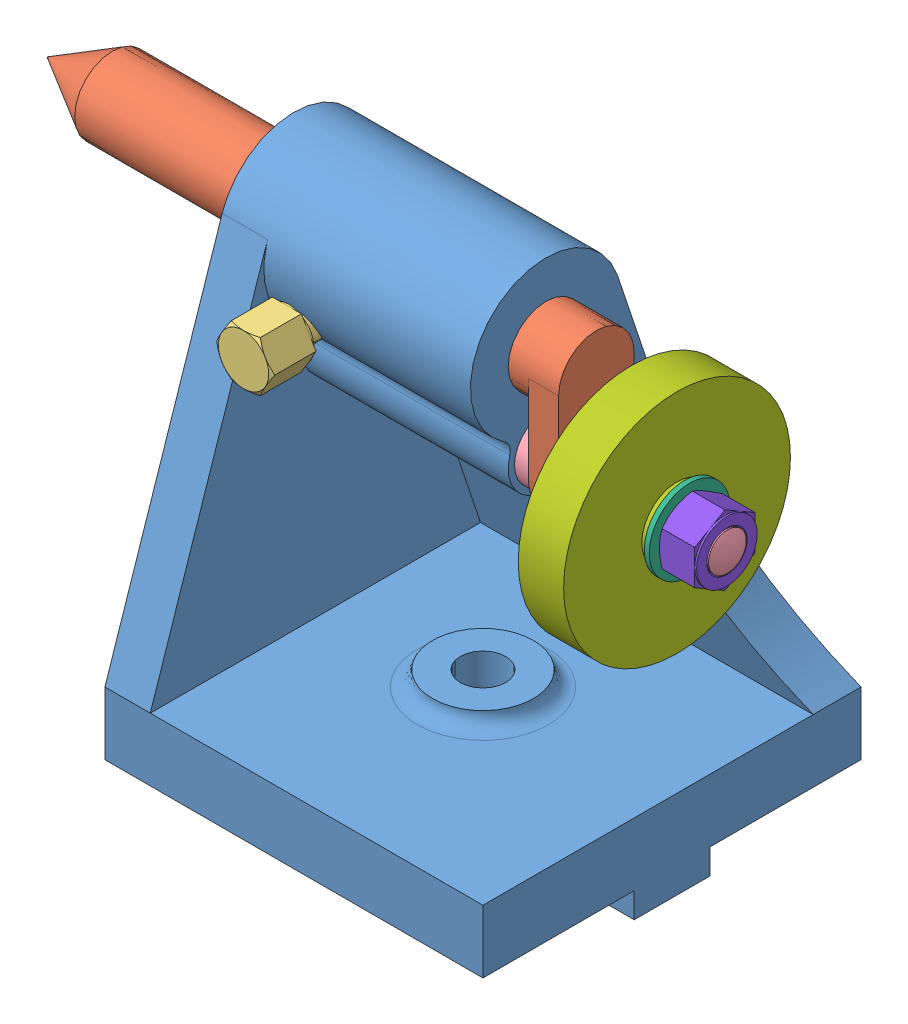
SolidWorks assembly Assem1, configuration Default. Lengths in mm.
Overall size (271.75 195 150).
8 component instances, 8 part files, 18 mates.
Components (placement in the parent):
- Part1-1: Part1 [Default] at (-27.6398 43.1033 183.0792) size (150 195 150)
- Part2-2: Part2 [Default] at (17.3602 198.1033 183.0792) x (0 -1 0) z (0 0 -1) size (65 217.98 30)
- Part3-2: Part3 [PreviewCfg] at (-72.6398 183.1033 233.0792) x (0 0 -1) z (0 -1 0) size (88 23.09 20)
- Part4-2: Part4 [Default] at (1.3602 163.1033 183.0792) size (135.54 25 25)
- Part5-2: Part5 [Default] at (34.8602 170.6033 183.0792) size (35 5 5)
- Part6-2: Part6 [Default] at (53.3602 163.1033 183.0792) x (0 -0.957696 -0.287782) z (1 0 0) size (32 32 2)
- Part7-2: Part7 [Default] at (40.3602 163.1033 183.0792) x (0 0 1) z (-1 0 0) size (90 90 35)
- hex nut style 1 gradeab_iso-1: hex nut style 1 gradeab_iso [ISO - 4032 - M16 - W - N] at (54.3602 163.1033 183.0792) x (0 0 1) z (-1 0 0) size (24 27.71 14.8)
Mates (geometry in assembly coordinates):
- Concentric3: concentric aligned: cylinder of Part1-1 through (-72.6398 183.1033 108.0792) axis (0 0 1) radius 6; cylinder of Part3-2 through (-72.6398 183.1033 233.0792) axis (0 0 1) radius 6
- Concentric5: concentric anti-aligned: cylinder of Part1-1 through (-2.6398 198.1033 183.0792) axis (-1 0 0) radius 15; cylinder of Part3-2 through (-84.1869 198.1033 183.0792) axis (1 0 0) radius 15
- Concentric6: concentric anti-aligned: cylinder of Part1-1 through (-72.6398 163.1033 183.0792) axis (1 0 0) radius 7.5; cylinder of Part4-2 through (-79.3247 163.1033 183.0792) axis (-1 0 0) radius 7.5
- Concentric7: concentric anti-aligned: cylinder of Part1-1 through (-2.6398 198.1033 183.0792) axis (-1 0 0) radius 15; cylinder of Part2-2 through (5.3602 198.1033 183.0792) axis (1 0 0) radius 15
- Concentric8: concentric anti-aligned: cylinder of Part2-2 through (5.3602 163.1033 183.0792) axis (1 0 0) radius 7.5; cylinder of Part4-2 through (-79.3247 163.1033 183.0792) axis (-1 0 0) radius 7.5
- Coincident2: coincident anti-aligned: plane of Part2-2 through (5.3602 198.1033 183.0792) normal (-1 0 0); plane of Part4-2 through (5.3602 163.1033 183.0792) normal (1 0 0)
- Coincident3: coincident anti-aligned: plane of Part4-2 through (52.3602 168.1033 180.5792) normal (0 1 0); plane of Part5-2 through (52.3602 168.1033 185.5792) normal (0 -1 0)
- Coincident4: coincident anti-aligned: plane of Part4-2 through (52.3602 173.1033 180.5792) normal (-1 0 0); plane of Part5-2 through (52.3602 173.1033 185.5792) normal (1 0 0)
- Coincident5: coincident anti-aligned: plane of Part4-2 through (1.3602 163.1033 185.5792) normal (0 0 -1); plane of Part5-2 through (34.8602 170.6033 185.5792) normal (0 0 1)
- Concentric9: concentric aligned: cylinder of Part4-2 through (-79.3247 163.1033 183.0792) axis (-1 0 0) radius 7.5; cylinder of Part7-2 through (-2.4238 163.1033 183.0792) axis (-1 0 0) radius 7.5
- Coincident6: coincident anti-aligned: plane of Part5-2 through (17.3602 172.7533 185.5792) normal (-0.01 0.99995 0); plane of Part7-2 through (52.3602 173.1033 180.5792) normal (0.01 -0.99995 0)
- Concentric10: concentric aligned: cylinder of Part4-2 through (-79.3247 163.1033 183.0792) axis (-1 0 0) radius 7.5; cylinder of Part6-2 through (54.3602 163.1033 183.0792) axis (-1 0 0) radius 7.5
- Coincident7: coincident anti-aligned: plane of Part6-2 through (52.3602 163.1033 183.0792) normal (-1 0 0); plane of Part7-2 through (52.3602 177.1033 183.0792) normal (1 0 0)
- Concentric11: concentric aligned: cylinder of Part4-2 through (-79.3247 163.1033 183.0792) axis (-1 0 0) radius 7.5; cylinder of hex nut style 1 gradeab_iso-1 through (79.3977 163.1033 183.0792) axis (-1 0 0) radius 8
- Concentric12: concentric aligned: cylinder of Part4-2 through (-79.3247 163.1033 183.0792) axis (-1 0 0) radius 7.5; cylinder of hex nut style 1 gradeab_iso-1 through (69.1602 163.1033 183.0792) axis (-1 0 0) radius 7
- Coincident8: coincident anti-aligned: plane of Part6-2 through (54.3602 163.1033 183.0792) normal (1 0 0); plane of hex nut style 1 gradeab_iso-1 through (54.3602 176.9597 183.0792) normal (-1 0 0)
- Parallel3: parallel aligned: plane of Part5-2 through (34.8602 170.6033 183.0792) normal (0 1 0); plane of assembly through (0 0 0) normal (0 1 0)
- Coincident12: coincident anti-aligned: plane of Part1-1 through (-2.6398 198.1033 183.0792) normal (1 0 0); plane of Part4-2 through (-2.6398 163.1033 183.0792) normal (-1 0 0)
